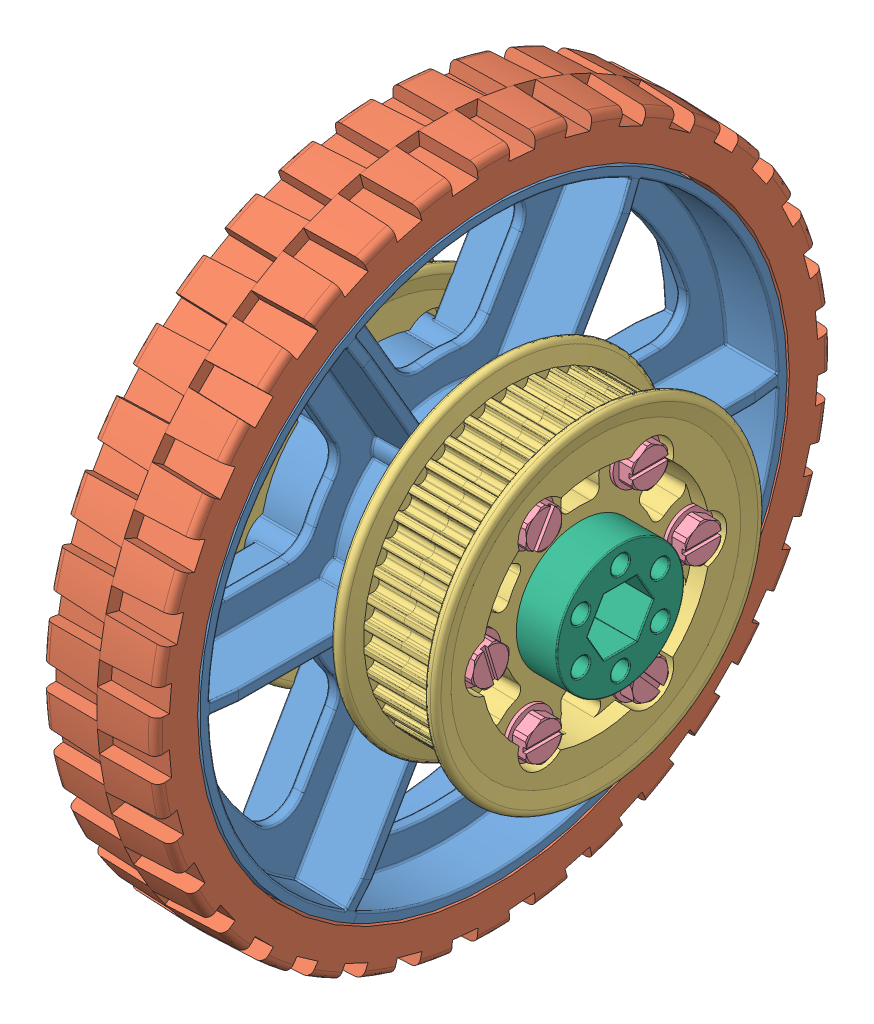
SolidWorks assembly Wheel HiGrip 6 in - Hub, Double Pulley, configuration Default. Lengths in mm.
Overall size (81.42 152.4 152.4).
21 component instances, 6 part files, 42 mates.
Components (placement in the parent):
- Wheel HiGrip 6 in-1: Wheel HiGrip 6 in [Default] at (83.7987 67.439 110.9939) size (35.05 152.4 152.4)
  - Wheel HiGrip 6 in_Wheel-1: Wheel HiGrip 6 in_Wheel [Default] at (-52.6446 9.4231 21.378) size (35.05 132.08 132.08)
  - Wheel HiGrip 6 in_Tread-1: Wheel HiGrip 6 in_Tread [Default] at (-65.3446 9.4231 21.378) x (0 0 -1) z (1 0 0) size (152.4 152.4 25.58)
- Half Pulley 42t 5 mm HTD-1: Half Pulley 42t 5 mm HTD [Default] at (47.6006 76.862 132.3719) x (1 0 0) z (0 -0.5 0.866025) size (13 74.23 74.23)
- Half Pulley 42t 5 mm HTD-2: Half Pulley 42t 5 mm HTD [Default] at (64.263 76.862 132.3719) x (-1 0 0) z (0 -0.499927 0.866067) size (13 74.23 74.23)
- 10-24 x 1.25 in Thread Forming Screw-1: 10-24 x 1.25 in Thread Forming Screw [93882A213] at (63.247 76.8605 108.5602) x (0 0 -1) z (1 0 0) size (10.52 10.52 35.59)
- 10-24 x 1.25 in Thread Forming Screw-2: 10-24 x 1.25 in Thread Forming Screw [93882A213] at (63.247 97.4833 120.4656) x (0 0 -1) z (1 0 0) size (10.52 10.52 35.59)
- 10-24 x 1.25 in Thread Forming Screw-3: 10-24 x 1.25 in Thread Forming Screw [93882A213] at (63.247 56.2398 144.2799) x (0 0 -1) z (1 0 0) size (10.52 10.52 35.59)
- 10-24 x 1.25 in Thread Forming Screw-4: 10-24 x 1.25 in Thread Forming Screw [93882A213] at (63.247 76.8625 156.1852) x (0 -0.95788 -0.287168) z (1 0 0) size (10.52 10.52 35.59)
- 10-24 x 1.25 in Thread Forming Screw-5: 10-24 x 1.25 in Thread Forming Screw [93882A213] at (63.247 97.4843 144.2781) x (0 -0.868976 0.494854) z (1 0 0) size (10.52 10.52 35.59)
- 10-24 x 1.25 in Thread Forming Screw-6: 10-24 x 1.25 in Thread Forming Screw [93882A213] at (63.247 56.2388 120.4674) x (0 -0.748729 -0.662876) z (1 0 0) size (10.52 10.52 35.59)
- Half Pulley 42t 5 mm HTD-3: Half Pulley 42t 5 mm HTD [Default] at (-1.9548 76.8628 132.3714) x (1 0 0) z (0 -1 -0.000063) size (13 74.23 74.23)
- Half Pulley 42t 5 mm HTD-4: Half Pulley 42t 5 mm HTD [Default] at (14.7076 76.8628 132.3714) x (-1 0 0) z (0 -1 0.000021) size (13 74.23 74.23)
- Hex Hub 500 EX-1: Hex Hub 500 EX [Default] at (-8.3048 76.8628 132.3714) x (0 -0.866025 -0.5) z (0 -0.5 0.866025) size (55.37 25.4 51.33)
- 10-24 x 1.25 in Thread Forming Screw-7: 10-24 x 1.25 in Thread Forming Screw [93882A213] at (-5.2568 97.485 120.4652) x (0 0 1) z (-1 0 0) size (10.52 10.52 35.59)
- 10-24 x 1.25 in Thread Forming Screw-8: 10-24 x 1.25 in Thread Forming Screw [93882A213] at (-5.2568 76.8628 108.5589) x (0 0 1) z (-1 0 0) size (10.52 10.52 35.59)
- 10-24 x 1.25 in Thread Forming Screw-9: 10-24 x 1.25 in Thread Forming Screw [93882A213] at (-5.2568 56.2406 120.4652) x (0 0 1) z (-1 0 0) size (10.52 10.52 35.59)
- 10-24 x 1.25 in Thread Forming Screw-10: 10-24 x 1.25 in Thread Forming Screw [93882A213] at (-5.2568 97.485 144.2777) x (0 -0.99374 -0.111715) z (-1 0 0) size (10.52 10.52 35.59)
- 10-24 x 1.25 in Thread Forming Screw-11: 10-24 x 1.25 in Thread Forming Screw [93882A213] at (-5.2568 56.2406 144.2777) x (0 -0.138911 0.990305) z (-1 0 0) size (10.52 10.52 35.59)
- 10-24 x 1.25 in Thread Forming Screw-12: 10-24 x 1.25 in Thread Forming Screw [93882A213] at (-5.2568 76.8628 156.1839) x (0 -0.98811 -0.15375) z (-1 0 0) size (10.52 10.52 35.59)
- Hex Spacer 0.57 in x 0.5 ID-1: Hex Spacer 0.57 in x 0.5 ID [Default] at (57.8495 76.862 132.3719) x (0 -0.866025 -0.5) z (0 -0.5 0.866025) size (28.55 14.48 28.55)
Mates (geometry in assembly coordinates):
- Concentric1: concentric anti-aligned: cylinder of Wheel HiGrip 6 in-1/Wheel HiGrip 6 in_Wheel-1 through (42.2666 76.862 132.3719) axis (1 0 0) radius 14.2875; cylinder of Half Pulley 42t 5 mm HTD-1 through (54.0141 76.862 132.3719) axis (-1 0 0) radius 14.2875
- Concentric4: concentric aligned: cylinder of Half Pulley 42t 5 mm HTD-1 through (57.2018 56.2388 120.4674) axis (-1 0 0) radius 4.1275; cylinder of Half Pulley 42t 5 mm HTD-2 through (57.3288 56.2388 120.4674) axis (-1 0 0) radius 4.1529
- Concentric5: concentric aligned: circle of Half Pulley 42t 5 mm HTD-1; cylinder of Half Pulley 42t 5 mm HTD-2 through (54.6618 97.4843 144.2781) axis (1 0 0) radius 4.1275
- Coincident2: coincident anti-aligned: plane of Half Pulley 42t 5 mm HTD-1 through (55.9318 104.6844 148.5781) normal (1 0 0); plane of Half Pulley 42t 5 mm HTD-2 through (55.9318 48.9145 116.3824) normal (-1 0 0)
- Concentric8: concentric anti-aligned: cylinder of Half Pulley 42t 5 mm HTD-2 through (55.9318 97.4833 120.4656) axis (1 0 0) radius 2.54; cylinder of 10-24 x 1.25 in Thread Forming Screw-2 through (64.0141 97.4833 120.4656) axis (-1 0 0) radius 5.2578
- Concentric9: concentric anti-aligned: cylinder of Half Pulley 42t 5 mm HTD-2 through (55.9318 76.8605 108.5602) axis (1 0 0) radius 2.54; circle of 10-24 x 1.25 in Thread Forming Screw-1
- Concentric10: concentric anti-aligned: cylinder of Half Pulley 42t 5 mm HTD-2 through (55.9318 56.2388 120.4674) axis (1 0 0) radius 2.54; cylinder of 10-24 x 1.25 in Thread Forming Screw-6 through (64.0141 56.2388 120.4674) axis (-1 0 0) radius 5.2578
- Concentric11: concentric anti-aligned: cylinder of Half Pulley 42t 5 mm HTD-2 through (55.9318 56.2398 144.2799) axis (1 0 0) radius 2.54; circle of 10-24 x 1.25 in Thread Forming Screw-3
- Concentric12: concentric anti-aligned: cylinder of Half Pulley 42t 5 mm HTD-2 through (55.9318 76.8625 156.1852) axis (1 0 0) radius 2.54; circle of 10-24 x 1.25 in Thread Forming Screw-4
- Concentric13: concentric anti-aligned: cylinder of Half Pulley 42t 5 mm HTD-2 through (55.9318 97.4843 144.2781) axis (1 0 0) radius 2.54; circle of 10-24 x 1.25 in Thread Forming Screw-5
- Coincident5: coincident aligned: plane of 10-24 x 1.25 in Thread Forming Screw-4 through (67.0824 78.1785 151.7955) normal (1 0 0); plane of 10-24 x 1.25 in Thread Forming Screw-5 through (67.0824 95.2165 140.2958) normal (1 0 0)
- Coincident6: coincident aligned: plane of 10-24 x 1.25 in Thread Forming Screw-3 through (67.0824 60.8225 144.2799) normal (1 0 0); plane of 10-24 x 1.25 in Thread Forming Screw-4 through (67.0824 78.1785 151.7955) normal (1 0 0)
- Coincident7: coincident aligned: plane of 10-24 x 1.25 in Thread Forming Screw-3 through (67.0824 60.8225 144.2799) normal (1 0 0); plane of 10-24 x 1.25 in Thread Forming Screw-6 through (67.0824 59.2766 117.0361) normal (1 0 0)
- Coincident8: coincident aligned: plane of 10-24 x 1.25 in Thread Forming Screw-1 through (67.0824 81.4433 108.5602) normal (1 0 0); plane of 10-24 x 1.25 in Thread Forming Screw-6 through (67.0824 59.2766 117.0361) normal (1 0 0)
- Coincident9: coincident aligned: plane of 10-24 x 1.25 in Thread Forming Screw-1 through (67.0824 81.4433 108.5602) normal (1 0 0); plane of 10-24 x 1.25 in Thread Forming Screw-2 through (67.0824 102.066 120.4656) normal (1 0 0)
- Coincident10: coincident anti-aligned: plane of Half Pulley 42t 5 mm HTD-2 through (63.247 76.862 132.3719) normal (1 0 0); plane of 10-24 x 1.25 in Thread Forming Screw-5 through (63.247 95.2165 140.2958) normal (-1 0 0)
- Concentric14: concentric anti-aligned: cylinder of Half Pulley 42t 5 mm HTD-3 through (4.4587 76.8628 132.3714) axis (-1 0 0) radius 14.2875; cylinder of Half Pulley 42t 5 mm HTD-4 through (8.2941 76.8628 132.3714) axis (1 0 0) radius 14.2875
- Concentric15: concentric aligned: cylinder of Half Pulley 42t 5 mm HTD-3 through (4.9794 76.8613 156.1839) axis (1 0 0) radius 4.1529; cylinder of Half Pulley 42t 5 mm HTD-4 through (5.1064 76.8613 156.1839) axis (1 0 0) radius 4.1275
- Coincident11: coincident anti-aligned: plane of Half Pulley 42t 5 mm HTD-3 through (6.3764 76.737 164.5694) normal (1 0 0); plane of Half Pulley 42t 5 mm HTD-4 through (6.3764 76.7383 100.1735) normal (-1 0 0)
- Concentric16: concentric anti-aligned: cylinder of Wheel HiGrip 6 in-1/Wheel HiGrip 6 in_Wheel-1 through (20.0416 76.862 132.3719) axis (-1 0 0) radius 14.2875; cylinder of Half Pulley 42t 5 mm HTD-4 through (8.2941 76.8628 132.3714) axis (1 0 0) radius 14.2875
- Coincident13: coincident anti-aligned: plane of Wheel HiGrip 6 in-1/Wheel HiGrip 6 in_Wheel-1 through (13.6916 76.862 132.3719) normal (-1 0 0); plane of Half Pulley 42t 5 mm HTD-4 through (13.6916 76.8628 132.3714) normal (1 0 0)
- Concentric22: concentric aligned: cylinder of Half Pulley 42t 5 mm HTD-3 through (4.4587 76.8628 132.3714) axis (-1 0 0) radius 14.2875; cylinder of Hex Hub 500 EX-1 through (17.0952 76.8628 132.3714) axis (-1 0 0) radius 12.1666
- Concentric23: concentric anti-aligned: cylinder of Half Pulley 42t 5 mm HTD-3 through (6.3764 97.4843 120.4656) axis (-1 0 0) radius 2.54; cylinder of Hex Hub 500 EX-1 through (-8.3048 97.485 120.4652) axis (1 0 0) radius 2.5908
- Coincident14: coincident anti-aligned: plane of Half Pulley 42t 5 mm HTD-3 through (-0.9388 76.8628 132.3714) normal (-1 0 0); plane of Hex Hub 500 EX-1 through (-0.9388 109.8584 151.4214) normal (1 0 0)
- Concentric24: concentric aligned: cylinder of Hex Hub 500 EX-1 through (-8.3048 97.485 120.4652) axis (1 0 0) radius 2.5908; cylinder of 10-24 x 1.25 in Thread Forming Screw-7 through (-6.0239 97.485 120.4652) axis (1 0 0) radius 5.2578
- Concentric25: concentric aligned: cylinder of Hex Hub 500 EX-1 through (-8.3048 76.8628 108.5589) axis (1 0 0) radius 2.5908; circle of 10-24 x 1.25 in Thread Forming Screw-8
- Concentric26: concentric aligned: cylinder of Hex Hub 500 EX-1 through (-8.3048 56.2406 120.4652) axis (1 0 0) radius 2.5908; cylinder of 10-24 x 1.25 in Thread Forming Screw-9 through (-6.0239 56.2406 120.4652) axis (1 0 0) radius 5.2578
- Concentric27: concentric aligned: cylinder of Hex Hub 500 EX-1 through (-8.3048 56.2406 144.2777) axis (1 0 0) radius 2.5908; circle of 10-24 x 1.25 in Thread Forming Screw-11
- Concentric28: concentric aligned: cylinder of Hex Hub 500 EX-1 through (-8.3048 76.8628 156.1839) axis (1 0 0) radius 2.5908; circle of 10-24 x 1.25 in Thread Forming Screw-12
- Concentric29: concentric aligned: cylinder of Hex Hub 500 EX-1 through (-8.3048 97.485 144.2777) axis (1 0 0) radius 2.5908; circle of 10-24 x 1.25 in Thread Forming Screw-10
- Coincident15: coincident aligned: plane of 10-24 x 1.25 in Thread Forming Screw-7 through (-9.0922 102.0677 120.4652) normal (-1 0 0); plane of 10-24 x 1.25 in Thread Forming Screw-8 through (-9.0922 81.4455 108.5589) normal (-1 0 0)
- Coincident16: coincident aligned: plane of 10-24 x 1.25 in Thread Forming Screw-8 through (-9.0922 81.4455 108.5589) normal (-1 0 0); plane of 10-24 x 1.25 in Thread Forming Screw-9 through (-9.0922 60.8233 120.4652) normal (-1 0 0)
- Coincident17: coincident aligned: plane of 10-24 x 1.25 in Thread Forming Screw-9 through (-9.0922 60.8233 120.4652) normal (-1 0 0); plane of 10-24 x 1.25 in Thread Forming Screw-11 through (-9.0922 60.7788 144.9143) normal (-1 0 0)
- Coincident18: coincident aligned: plane of 10-24 x 1.25 in Thread Forming Screw-11 through (-9.0922 60.7788 144.9143) normal (-1 0 0); plane of 10-24 x 1.25 in Thread Forming Screw-12 through (-9.0922 76.1582 160.7122) normal (-1 0 0)
- Coincident19: coincident aligned: plane of 10-24 x 1.25 in Thread Forming Screw-10 through (-9.0922 96.9731 148.8317) normal (-1 0 0); plane of 10-24 x 1.25 in Thread Forming Screw-12 through (-9.0922 76.1582 160.7122) normal (-1 0 0)
- Coincident20: coincident anti-aligned: plane of Hex Hub 500 EX-1 through (-5.2568 109.8584 151.4214) normal (-1 0 0); plane of 10-24 x 1.25 in Thread Forming Screw-7 through (-5.2568 102.0677 120.4652) normal (1 0 0)
- Concentric30: concentric anti-aligned: cylinder of Half Pulley 42t 5 mm HTD-2 through (57.8495 76.862 132.3719) axis (1 0 0) radius 14.2875; cylinder of Hex Spacer 0.57 in x 0.5 ID-1 through (72.3275 76.862 132.3719) axis (-1 0 0) radius 14.2748
- Parallel1: parallel: plane of Hex Hub 500 EX-1 through (-8.3048 70.5001 128.6979) normal (0 0.5 0.866025); line of Hex Spacer 0.57 in x 0.5 ID-1 through (72.0691 70.4837 128.686) axis (0 0.866025 -0.5)
- Coincident22: coincident anti-aligned: plane of Half Pulley 42t 5 mm HTD-2 through (57.8495 76.862 132.3719) normal (1 0 0); circle of Hex Spacer 0.57 in x 0.5 ID-1
- Concentric31: concentric aligned: cylinder of Wheel HiGrip 6 in-1/Wheel HiGrip 6 in_Wheel-1 through (48.6166 97.4843 144.2781) axis (-1 0 0) radius 1.9939; cylinder of Half Pulley 42t 5 mm HTD-1 through (55.9318 97.4843 144.2781) axis (-1 0 0) radius 2.54
- Coincident23: coincident anti-aligned: plane of Wheel HiGrip 6 in-1/Wheel HiGrip 6 in_Wheel-1 through (48.6166 76.862 132.3719) normal (1 0 0); plane of Half Pulley 42t 5 mm HTD-1 through (48.6166 76.862 132.3719) normal (-1 0 0)
- Concentric32: concentric anti-aligned: cylinder of Wheel HiGrip 6 in-1/Wheel HiGrip 6 in_Wheel-1 through (48.6166 97.4843 120.4656) axis (-1 0 0) radius 1.9939; cylinder of Half Pulley 42t 5 mm HTD-4 through (6.3764 97.4843 120.4656) axis (1 0 0) radius 2.54
